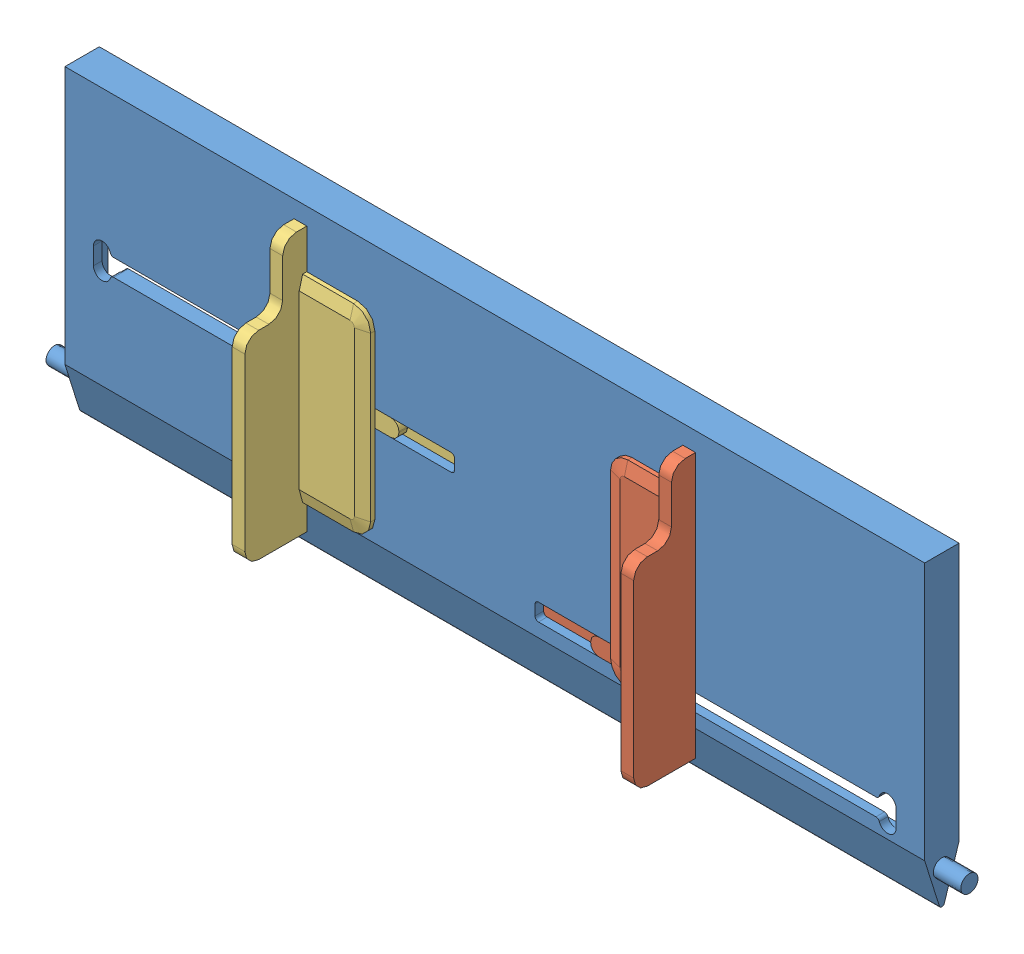
SolidWorks assembly Guidage, configuration Défaut. Lengths in mm.
Overall size (266 89.11 30.1).
6 component instances, 6 part files, 17 mates.
Components (placement in the parent):
- Guidage-1: Guidage [Défaut] at origin size (266 89.11 10)
- Guidage 1 Bas-1: Guidage 1 Bas [Défaut] at (-22.46 17.258 -1.5) size (131.16 77 24.5)
- Guidage 2 Millieu-1: Guidage 2 Millieu [Défaut] at (22.46 52.458 -1.5) x (-1 0 0) z (0 0 1) size (131.16 77 24.5)
- Roue à denture droite m=0,75 Z=18-1: Roue à denture droite m=0,75 Z=18 [Défaut] at (0 34.858 0) x (-0.905578 -0.424179 0) z (0 0 -1) size (18 18 6.5)
- Vis à tête hexagonale H M4 - 5-1: Vis à tête hexagonale H M4 - 5 [Défaut] at (0 34.858 -4.3) size (7 8.08 7.8)
- Rondelle plate Type Z - 4-1: Rondelle plate Type Z - 4 [Défaut] at (0 34.858 -3.5) x (0 0 -1) z (0.999349 0.036091 0) size (0.8 8 8)
Mates (geometry in assembly coordinates):
- Coïncidente1: coincident anti-aligned: plane of Guidage-1 through (125 15.858 2.5) normal (0 0 -1); plane of Roue à denture droite m=0,75 Z=18-1 through (0 34.858 2.5) normal (0 0 1)
- Coaxiale2: concentric aligned: cylinder of Guidage-1 through (0 34.858 -3.5) axis (0 0 1) radius 3.25; cylinder of Roue à denture droite m=0,75 Z=18-1 through (0 34.858 -2.5) axis (0 0 1) radius 2.625
- Coïncidente3: coincident anti-aligned: plane of Guidage-1 through (125 15.858 5) normal (0 0 1); plane of Guidage 1 Bas-1 through (90.2 22.358 5) normal (0 0 -1)
- Coïncidente4: coincident anti-aligned: plane of Guidage-1 through (110.8459 19.858 -5) normal (0 1 0); plane of Guidage 1 Bas-1 through (79.2 19.858 2.5) normal (0 -1 0)
- Coaxiale3: concentric aligned: cylinder of Guidage-1 through (0 34.858 -3.5) axis (0 0 1) radius 1.65; cylinder of Vis à tête hexagonale H M4 - 5-1 through (0 34.858 -4.3) axis (0 0 1) radius 2
- Coïncidente10: coincident anti-aligned: plane of Guidage-1 through (0 34.858 -3.5) normal (0 0 -1); plane of Rondelle plate Type Z - 4-1 through (-3.9974 34.7136 -3.5) normal (0 0 1)
- Coaxiale4: concentric aligned: cylinder of Guidage-1 through (0 34.858 -3.5) axis (0 0 1) radius 1.65; cylinder of Rondelle plate Type Z - 4-1 through (0 34.858 -3.5) axis (0 0 1) radius 2.15
- Coïncidente11: coincident anti-aligned: plane of Vis à tête hexagonale H M4 - 5-1 through (3.5 36.8787 -4.3) normal (0 0 1); plane of Rondelle plate Type Z - 4-1 through (-3.9974 34.7136 -4.3) normal (0 0 -1)
- Distance1: distance = 210 mm: plane of Guidage 1 Bas-1 through (54.6754 81.358 8) normal (-1 0 0); plane of Guidage 2 Millieu-1 through (-54.6754 81.858 8) normal (1 0 0)
- Symétrique1: symmetric aligned: plane of Guidage-1 through (0 0 0) normal (1 0 0); plane of Guidage 2 Millieu-1 through (105 81.358 8) normal (-1 0 0); plane of Guidage 1 Bas-1 through (-105 81.858 8) normal (1 0 0)
- Coïncidente14: coincident anti-aligned: plane of Guidage-1 through (125 15.858 5) normal (0 0 1); plane of Guidage 2 Millieu-1 through (-90.2 69.358 5) normal (0 0 -1)
- Coïncidente15: coincident anti-aligned: plane of Guidage-1 through (-110.8459 49.858 -5) normal (0 -1 0); plane of Guidage 2 Millieu-1 through (-79.2 49.858 2.5) normal (0 1 0)
- Coïncidente16: coincident aligned: plane of Guidage-1 through (0 0 0) normal (1 0 0)
- Coïncidente17: coincident aligned: plane of Guidage-1 through (0 0 0) normal (0 1 0)
- Coïncidente18: coincident aligned: plane of Guidage-1 through (0 0 0) normal (0 0 1)
- Coïncidente19: coincident anti-aligned: plane of Guidage 1 Bas-1 through (0 17.258 -1.5) normal (1 0 0); plane of Guidage 2 Millieu-1 through (0 52.458 -1.5) normal (-1 0 0)
- Distance2: distance = 210 mm anti-aligned: plane of Guidage 2 Millieu-1 through (-105 81.858 8) normal (1 0 0); plane of Guidage 1 Bas-1 through (105 81.358 8) normal (-1 0 0)
